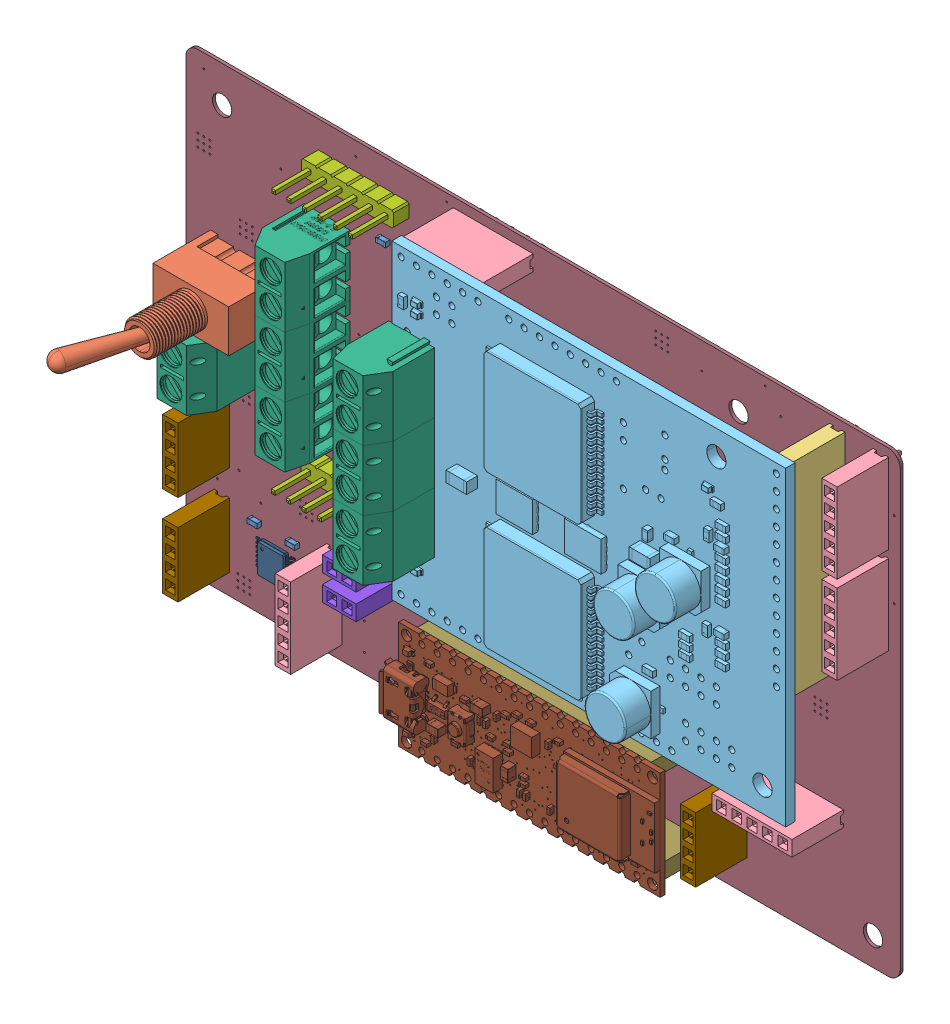
SolidWorks assembly r2dtf dev board rev 1, configuration Default. Lengths in mm.
Overall size (117.99 75.59 36.17).
64 component instances, 13 part files, 0 mates.
Components (placement in the parent):
- r2dtf dev board rev 1.step-1: r2dtf dev board rev 1.step [Default] at origin size (117.99 75.59 36.17)
  - C_0603_1608Metric.step-1: C_0603_1608Metric.step [Default] at (77.1 -104.9 0.54) size (1.6 0.8 0.8)
    - C_0603_1608Metric-0.step-1: C_0603_1608Metric-0.step [Default] at origin size (1.6 0.8 0.8)
  - MTS-101 6A 125VAC Mini Toggle Switch.step-1: MTS-101 6A 125VAC Mini Toggle Switch.step [Default] at (62.4 -88.65 0.54) x (1 0 0) z (0 -1 0) size (12.5 36.17 7)
    - MTS-101 6A 125VAC Mini Toggle Switch-1.step-1: MTS-101 6A 125VAC Mini Toggle Switch-1.step [Default] at origin size (12.5 36.17 7)
  - Sullins Female Header 13 x 1 _ _ _C131LFBN-RC.step-1: Sullins Female Header 13 x 1 _ _ _C131LFBN-RC.step [Default] at (158.3865 -61.2635 0.54) x (0 -1 0) z (-1 0 0) size (33.52 11.7 2.54)
    - _ _ _C131LFBN-RC.step-1: _ _ _C131LFBN-RC.step [Default] at origin size (33.52 11.7 2.54)
  - Sullins Female Header 5 x 1 _ _ _C051LFBN-RC.step-1: Sullins Female Header 5 x 1 _ _ _C051LFBN-RC.step [Default] at (109.4365 -61.5135 0.54) x (-1 0 0) z (0 1 0) size (13.2 11.7 2.54)
    - _ _ _C051LFBN-RC.step-1: _ _ _C051LFBN-RC.step [Default] at origin size (13.2 11.7 2.54)
  - Sullins Female Header 5 x 1 _ _ _C051LFBN-RC.step-2: Sullins Female Header 5 x 1 _ _ _C051LFBN-RC.step [Default] at (109.4365 -109.7635 0.54) x (-1 0 0) z (0 1 0) size (13.2 11.7 2.54)
    - _ _ _C051LFBN-RC.step-1: _ _ _C051LFBN-RC.step [Default] at origin size (13.2 11.7 2.54)
  - pololu-dual-vnh5019-motor-driver-shield.step-1: pololu-dual-vnh5019-motor-driver-shield.step [Default] at (161.1865 -61.2635 9.04) x (-1 0 0) z (0 0 1) size (65.02 51.31 7.67)
    - pololu-dual-vnh5019-notor-driver-shield-for-arduino.step-1: pololu-dual-vnh5019-notor-driver-shield-for-arduino.step [Default] at origin size (65.02 51.31 7.67)
  - Degson Screw Terminal 2P 5 mm DG301-5.0-02P-12-00AH.step-1: Degson Screw Terminal 2P 5 mm DG301-5.0-02P-12-00AH.step [Default] at (103.1865 -73.0135 10.54) x (0 -1 0) z (-1 0 0) size (10.6 14.3 7.6)
    - DG301-5.0-02P-12-00AH.step-1: DG301-5.0-02P-12-00AH.step [Default] at origin size (10.6 14.3 7.6)
  - Degson Screw Terminal 2P 5 mm DG301-5.0-02P-12-00AH.step-2: Degson Screw Terminal 2P 5 mm DG301-5.0-02P-12-00AH.step [Default] at (103.1865 -83.0135 10.54) x (0 -1 0) z (-1 0 0) size (10.6 14.3 7.6)
    - DG301-5.0-02P-12-00AH.step-1: DG301-5.0-02P-12-00AH.step [Default] at origin size (10.6 14.3 7.6)
  - Degson Screw Terminal 2P 5 mm DG301-5.0-02P-12-00AH.step-3: Degson Screw Terminal 2P 5 mm DG301-5.0-02P-12-00AH.step [Default] at (103.1865 -93.0135 10.54) x (0 -1 0) z (-1 0 0) size (10.6 14.3 7.6)
    - DG301-5.0-02P-12-00AH.step-1: DG301-5.0-02P-12-00AH.step [Default] at origin size (10.6 14.3 7.6)
  - Degson Screw Terminal 2P 5 mm DG301-5.0-02P-12-00AH.step-4: Degson Screw Terminal 2P 5 mm DG301-5.0-02P-12-00AH.step [Default] at (71.6 -103.25 0.54) x (0 1 0) z (1 0 0) size (10.6 14.3 7.6)
    - DG301-5.0-02P-12-00AH.step-1: DG301-5.0-02P-12-00AH.step [Default] at origin size (10.6 14.3 7.6)
  - PinHeader_1x06_P2.54mm_Vertical.step-1: PinHeader_1x06_P2.54mm_Vertical.step [Default] at (87.6554 -65.659 0.54) x (0 -1 0) z (0 0 1) size (2.54 15.24 11.54)
    - PinHeader_1x06_P254mm_Vertical.step-1: PinHeader_1x06_P254mm_Vertical.step [Default] at origin size (2.54 15.24 11.54)
  - Degson Screw Terminal 2P 5 mm DG301-5.0-02P-12-00AH.step-5: Degson Screw Terminal 2P 5 mm DG301-5.0-02P-12-00AH.step [Default] at (64.1 -93.25 0.54) x (0 -1 0) z (-1 0 0) size (10.6 14.3 7.6)
    - DG301-5.0-02P-12-00AH.step-1: DG301-5.0-02P-12-00AH.step [Default] at origin size (10.6 14.3 7.6)
  - PinHeader_1x06_P2.54mm_Vertical.step-2: PinHeader_1x06_P2.54mm_Vertical.step [Default] at (74.88 -108.6866 0.54) x (0 1 0) z (0 0 1) size (2.54 15.24 11.54)
    - PinHeader_1x06_P254mm_Vertical.step-1: PinHeader_1x06_P254mm_Vertical.step [Default] at origin size (2.54 15.24 11.54)
  - Sullins Female Header 2 x 1_ _ _C021LFBN-RC.step-1: Sullins Female Header 2 x 1_ _ _C021LFBN-RC.step [Default] at (88.6968 -113.4661 0.54) x (-1 0 0) z (0 1 0) size (5.58 11.7 2.54)
    - _ _ _C021LFBN-RC.step-1: _ _ _C021LFBN-RC.step [Default] at origin size (5.58 11.7 2.54)
  - C_0603_1608Metric.step-2: C_0603_1608Metric.step [Default] at (63.8 -122.5 0.54) size (1.6 0.8 0.8)
    - C_0603_1608Metric-0.step-1: C_0603_1608Metric-0.step [Default] at origin size (1.6 0.8 0.8)
  - Sullins Female Header 4 x 1 _ _ _C041LFBN-RC.step-1: Sullins Female Header 4 x 1 _ _ _C041LFBN-RC.step [Default] at (142.2146 -119.5324 0.54) x (0 -1 0) z (-1 0 0) size (10.66 11.7 2.54)
    - _ _ _C041LFBN-RC.step-1: _ _ _C041LFBN-RC.step [Default] at origin size (10.66 11.7 2.54)
  - TSSOP-14_4.4x5mm_P0.65mm.step-1: TSSOP-14_4.4x5mm_P0.65mm.step [Default] at (67 -126.8 0.54) size (6.4 5 1)
    - TSSOP_14_44x5mm_P065mm.step-1: TSSOP_14_44x5mm_P065mm.step [Default] at origin size (6.4 5 1)
  - Sullins Female Header 4 x 1 _ _ _C041LFBN-RC.step-2: Sullins Female Header 4 x 1 _ _ _C041LFBN-RC.step [Default] at (56.73 -106.5555 0.54) x (0 -1 0) z (-1 0 0) size (10.66 11.7 2.54)
    - _ _ _C041LFBN-RC.step-1: _ _ _C041LFBN-RC.step [Default] at origin size (10.66 11.7 2.54)
  - Degson Screw Terminal 2P 5 mm DG301-5.0-02P-12-00AH.step-6: Degson Screw Terminal 2P 5 mm DG301-5.0-02P-12-00AH.step [Default] at (71.6 -83.25 0.54) x (0 1 0) z (1 0 0) size (10.6 14.3 7.6)
    - DG301-5.0-02P-12-00AH.step-1: DG301-5.0-02P-12-00AH.step [Default] at origin size (10.6 14.3 7.6)
  - Sullins Female Header 2 x 1_ _ _C021LFBN-RC.step-2: Sullins Female Header 2 x 1_ _ _C021LFBN-RC.step [Default] at (88.6968 -117.7161 0.54) x (-1 0 0) z (0 1 0) size (5.58 11.7 2.54)
    - _ _ _C021LFBN-RC.step-1: _ _ _C021LFBN-RC.step [Default] at origin size (5.58 11.7 2.54)
  - C_0603_1608Metric.step-3: C_0603_1608Metric.step [Default] at (85 -71.7 0.54) x (-1 0 0) z (0 0 1) size (1.6 0.8 0.8)
    - C_0603_1608Metric-0.step-1: C_0603_1608Metric-0.step [Default] at origin size (1.6 0.8 0.8)
  - Sullins Female Header 4 x 1 _ _ _C041LFBN-RC.step-3: Sullins Female Header 4 x 1 _ _ _C041LFBN-RC.step [Default] at (56.73 -121.5 0.54) x (0 -1 0) z (-1 0 0) size (10.66 11.7 2.54)
    - _ _ _C041LFBN-RC.step-1: _ _ _C041LFBN-RC.step [Default] at origin size (10.66 11.7 2.54)
  - Nano33BLE.step-1: Nano33BLE.step [Default] at (96.53 -133.77 9.04) size (43.8 17.78 3.58)
    - Nano33BLE v7.step-1: Nano33BLE v7.step [Default] at origin size (43.8 17.78 3.58)
  - Sullins Female Header 15 x 1_ _ _C151LFBN-RC.step-1: Sullins Female Header 15 x 1_ _ _C151LFBN-RC.step [Default] at (137.43 -131.27 0.54) x (-1 0 0) z (0 1 0) size (38.6 11.7 2.54)
    - _ _ _C151LFBN-RC.step-1: _ _ _C151LFBN-RC.step [Default] at origin size (38.6 11.7 2.54)
  - Sullins Female Header 15 x 1_ _ _C151LFBN-RC.step-2: Sullins Female Header 15 x 1_ _ _C151LFBN-RC.step [Default] at (137.43 -115.97 0.54) x (-1 0 0) z (0 1 0) size (38.6 11.7 2.54)
    - _ _ _C151LFBN-RC.step-1: _ _ _C151LFBN-RC.step [Default] at origin size (38.6 11.7 2.54)
  - Degson Screw Terminal 2P 5 mm DG301-5.0-02P-12-00AH.step-7: Degson Screw Terminal 2P 5 mm DG301-5.0-02P-12-00AH.step [Default] at (71.6 -93.25 0.54) x (0 1 0) z (1 0 0) size (10.6 14.3 7.6)
    - DG301-5.0-02P-12-00AH.step-1: DG301-5.0-02P-12-00AH.step [Default] at origin size (10.6 14.3 7.6)
  - Sullins Female Header 5 x 1 _ _ _C051LFBN-RC.step-3: Sullins Female Header 5 x 1 _ _ _C051LFBN-RC.step [Default] at (168.1305 -74.4645 0.54) x (0 1 0) z (1 0 0) size (13.2 11.7 2.54)
    - _ _ _C051LFBN-RC.step-1: _ _ _C051LFBN-RC.step [Default] at origin size (13.2 11.7 2.54)
  - Sullins Female Header 5 x 1 _ _ _C051LFBN-RC.step-4: Sullins Female Header 5 x 1 _ _ _C051LFBN-RC.step [Default] at (147.4644 -117.9436 0.54) x (1 0 0) z (0 -1 0) size (13.2 11.7 2.54)
    - _ _ _C051LFBN-RC.step-1: _ _ _C051LFBN-RC.step [Default] at origin size (13.2 11.7 2.54)
  - Sullins Female Header 5 x 1 _ _ _C051LFBN-RC.step-5: Sullins Female Header 5 x 1 _ _ _C051LFBN-RC.step [Default] at (75.33 -120 0.54) x (0 -1 0) z (-1 0 0) size (13.2 11.7 2.54)
    - _ _ _C051LFBN-RC.step-1: _ _ _C051LFBN-RC.step [Default] at origin size (13.2 11.7 2.54)
  - Sullins Female Header 5 x 1 _ _ _C051LFBN-RC.step-6: Sullins Female Header 5 x 1 _ _ _C051LFBN-RC.step [Default] at (168.1305 -88.934 0.54) x (0 1 0) z (1 0 0) size (13.2 11.7 2.54)
    - _ _ _C051LFBN-RC.step-1: _ _ _C051LFBN-RC.step [Default] at origin size (13.2 11.7 2.54)
  - C_0603_1608Metric.step-4: C_0603_1608Metric.step [Default] at (70 -122.5 0.54) x (-1 0 0) z (0 0 1) size (1.6 0.8 0.8)
    - C_0603_1608Metric-0.step-1: C_0603_1608Metric-0.step [Default] at origin size (1.6 0.8 0.8)
  - r2dtf dev board rev 1 PCB.step-1: r2dtf dev board rev 1 PCB.step [Default] at origin size (117.99 75.59 0.49)
